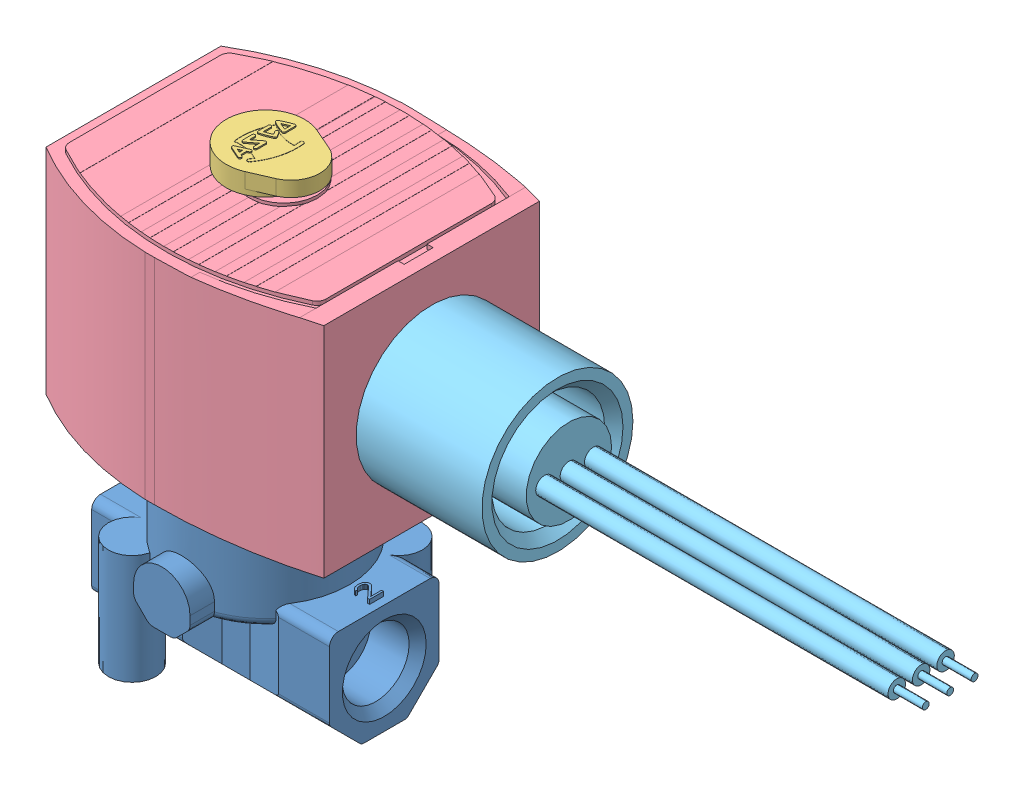
SolidWorks assembly Assem1, configuration Default. Lengths in mm.
Overall size (86.36 78.78 42.93).
5 component instances, 5 part files, 0 mates.
Components (placement in the parent):
- 295525-002M6-1: 295525-002M6 [Default] at origin size (39.61 28.82 32.29)
- 295530-004-1-42_52-1: 295530-004-1-42_52 [Default] at (0 13.8564 0) x (-1 0 0) z (0 0 -1) size (29.33 8.27 25.4)
- 238754-500_30_32-1: 238754-500_30_32 [Default] at (86.1568 55.6164 -0.1884) x (-1 0 0) z (0 0 -1) size (15.58 3.57 13.03)
- 238754-500-1: 238754-500 [Default] at (86.1568 55.9064 -0.1884) x (-1 0 0) z (0 0 -1) size (49.66 36.75 42.93)
- 238754-500_2-1: 238754-500_2 [Default] at (86.1568 55.9364 -0.0942) x (-1 0 0) z (0 0 -1) size (86.36 25.15 25.15)
